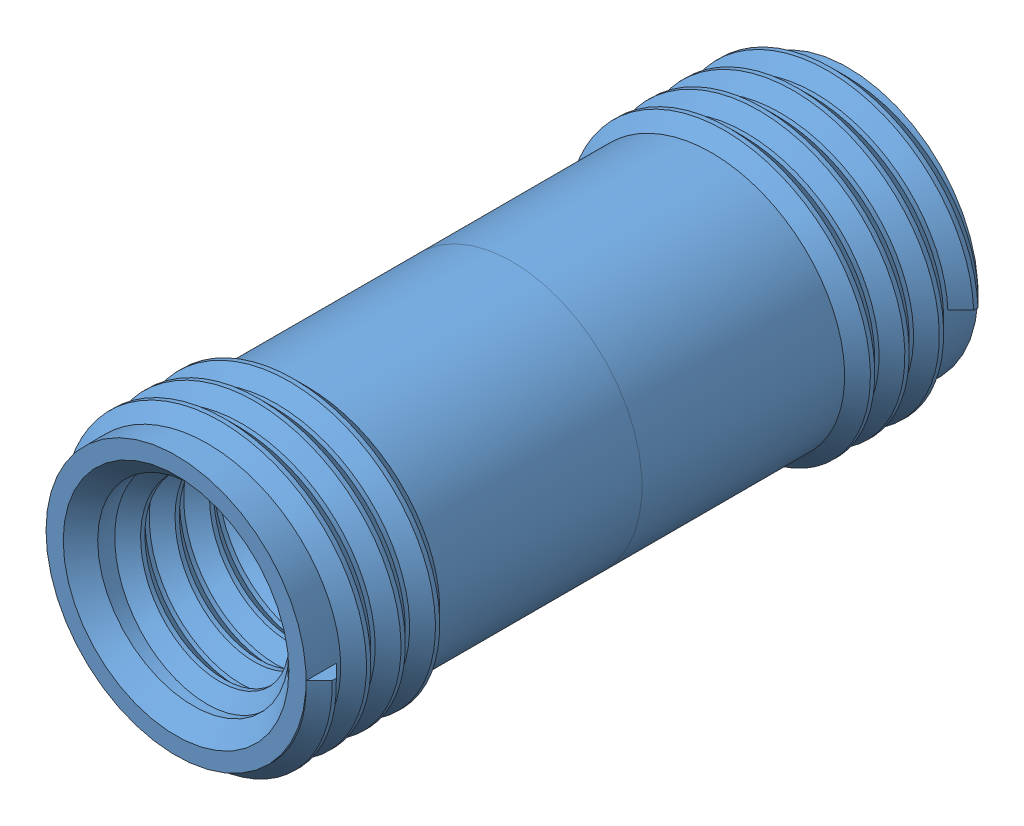
SolidWorks assembly 中轴（大）装配体, configuration 默认. Lengths in mm.
Overall size (33.21 33.2 78).
2 component instances, 1 part files, 4 mates.
Components (placement in the parent):
- 中轴（大）-1: 中轴（大） [默认] at origin size (33.21 33.2 39)
- 中轴（大）-2: 中轴（大） [默认] x (1 0 0) z (0 0 -1) size (33.21 33.2 39)
Mates (geometry in assembly coordinates):
- 重合4: coincident anti-aligned: plane of 新中轴外-1 through (0 0 0) normal (0 0 -1); plane of 新中轴外-2 through (0 0 0) normal (0 0 1)
- 同心3: concentric anti-aligned: circle of 新中轴外-1; circle of 新中轴外-2
- 重合6: coincident anti-aligned: plane of 新中轴外-1 through (-16.225 0 23.875) normal (0 1 0); plane of 新中轴外-2 through (-16.225 0 -23.875) normal (0 -1 0)
- 重合8: coincident anti-aligned: plane of 新中轴外-1 through (-16.225 0 23.875) normal (0 1 0); plane of 新中轴外-2 through (-16.225 0 -23.875) normal (0 -1 0)
